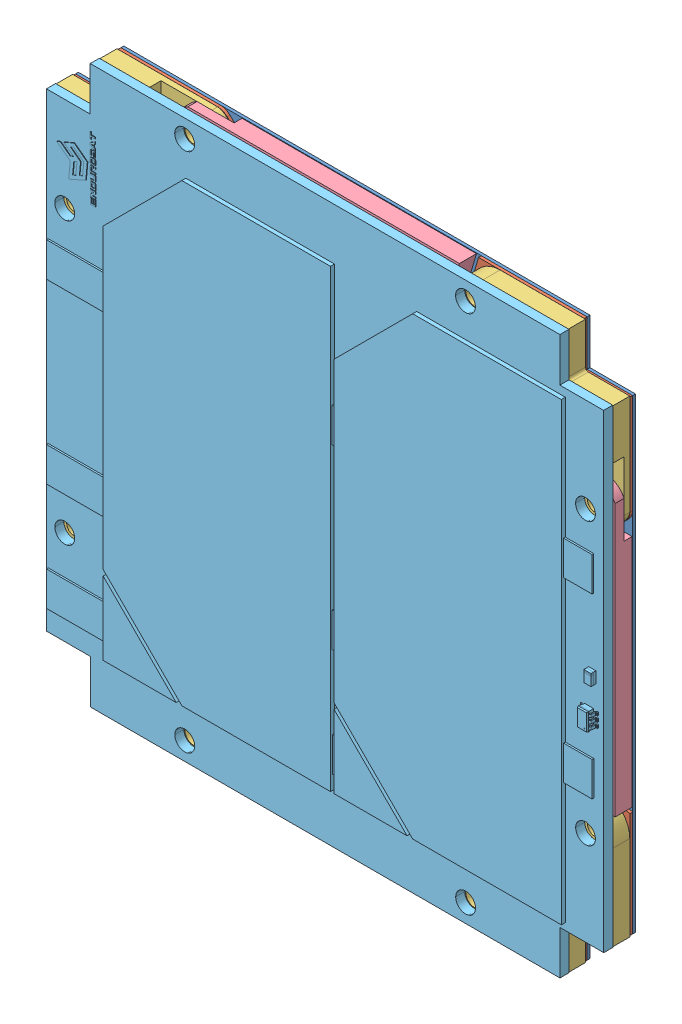
SolidWorks assembly EnduroSat_UHF_antenna+ZMTQ_SolarPanel, configuration Default. Lengths in mm.
Overall size (98.03 98.03 13.56).
9 component instances, 5 part files, 0 mates.
Components (placement in the parent):
- EnduroSat_UHF_antenna+ZMTQ_SolarPanel.STEP-1: EnduroSat_UHF_antenna+ZMTQ_SolarPanel.STEP [Default] at origin size (98.03 98.03 13.56)
  - ES_UHF_Ant_Feed_v6_1.STEP-1: ES_UHF_Ant_Feed_v6_1.STEP [Default] at (37.8755 60.8085 69.6819) size (98 98 8.25)
  - ES_UHF_Ant_v6_1_Upper.STEP-1: ES_UHF_Ant_v6_1_Upper.STEP [Default] at (37.8755 60.8085 70.1842) size (98 98 0.5)
  - UHF_frame_Rev1.2_stepc.STEP-1: UHF_frame_Rev1.2_stepc.STEP [Default] at (37.8762 60.7984 70.1842) size (98.01 98.01 3)
  - vhf_uhf_door_19042017_2.STEP-1: vhf_uhf_door_19042017_2.STEP [Default] at (113.2674 3.9646 69.7842) x (0 1 0) z (0 0 1) size (53.47 9.32 3)
  - vhf_uhf_door_19042017_2.STEP-2: vhf_uhf_door_19042017_2.STEP [Default] at (94.7101 136.1895 69.7842) x (-1 0 0) z (0 0 1) size (53.47 9.32 3)
  - vhf_uhf_door_19042017_2.STEP-3: vhf_uhf_door_19042017_2.STEP [Default] at (-37.5149 117.6323 69.7842) x (0 -1 0) z (0 0 1) size (53.47 9.32 3)
  - vhf_uhf_door_19042017_2.STEP-4: vhf_uhf_door_19042017_2.STEP [Default] at (-18.9576 -14.5927 69.7842) x (1 0 0) z (0 0 1) size (53.47 9.32 3)
  - Top_Panel_Rev1_5_090617.STEP-1: Top_Panel_Rev1_5_090617.STEP [Default] at (37.8856 60.8034 74.7842) x (1 0.000204 0) z (0 0 1) size (98 98 8.6)
